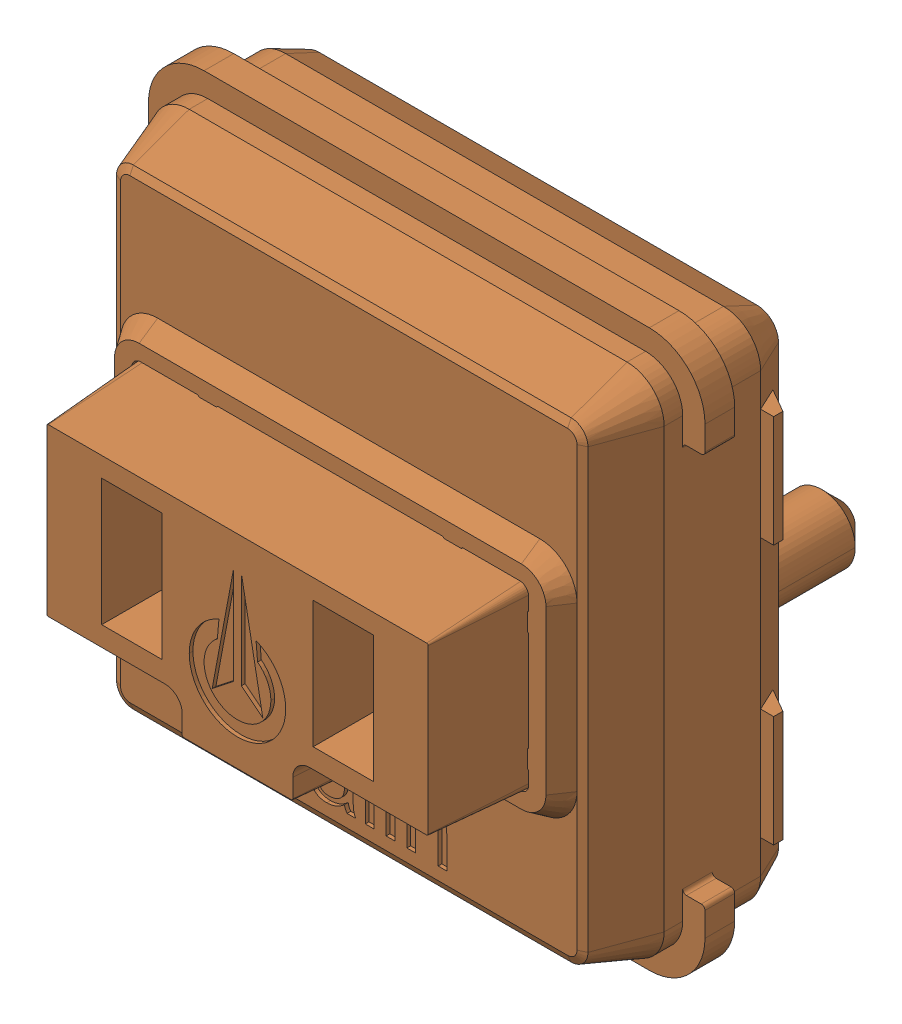
SolidWorks assembly SW3_1.step, configuration Default. Lengths in mm.
Overall size (15 15 11.1).
2 component instances, 2 part files, 0 mates.
Components (placement in the parent):
- WS2812-2020_1.step-3: WS2812-2020_1.step [Default] at (538.4468 231.0345 0.3) x (1 0 0) z (0 -1 0) size (2.2 0.86 2)
- Kailh LP Choc Burnt Orange_1.step-3: Kailh LP Choc Burnt Orange_1.step [Default] at (538.3402 226.3933 2.7) x (0 -1 0) z (-1 0 0) size (15 11.1 15)
